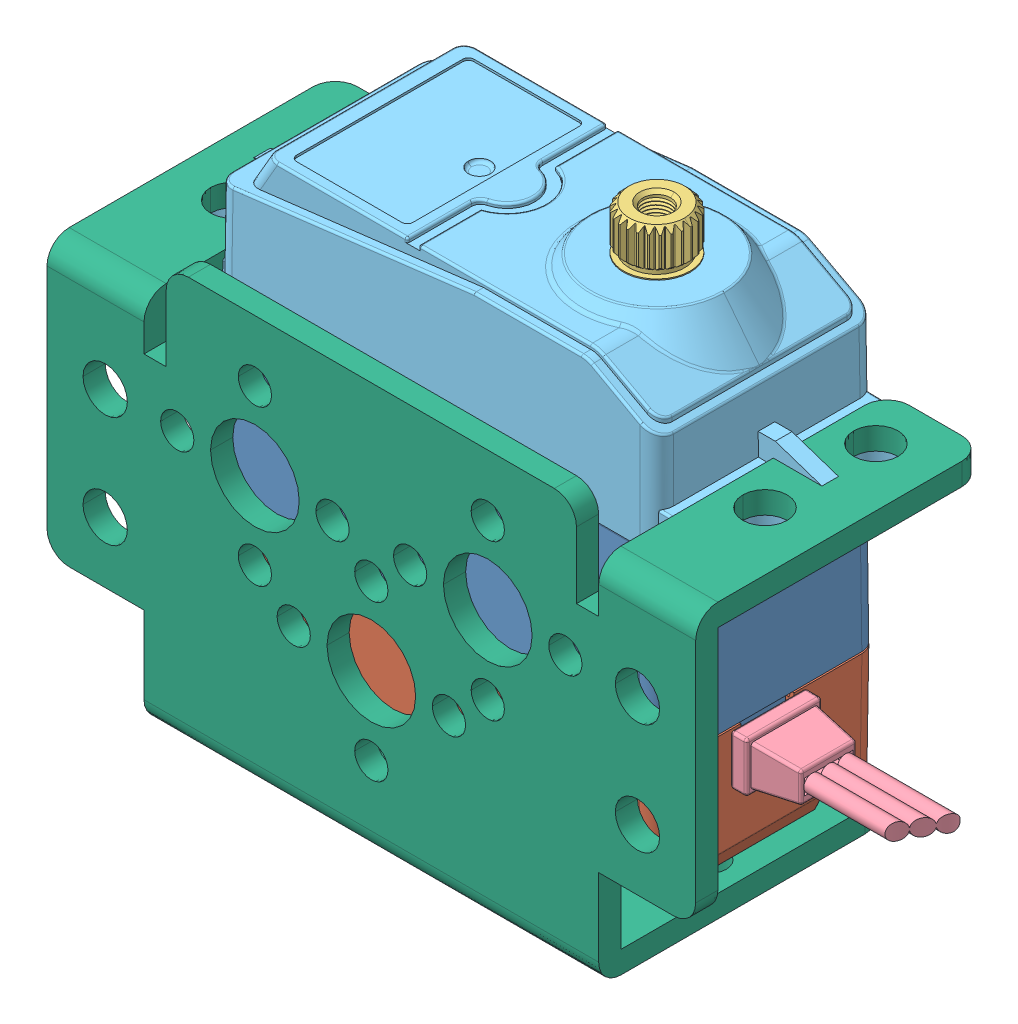
SolidWorks assembly 单轴舵机, configuration 默认. Lengths in mm.
Overall size (63.51 47.5 26.53).
9 component instances, 7 part files, 3 mates.
Components (placement in the parent):
- 单轴舵机.STEP-1: 单轴舵机.STEP [默认] at origin size (62.21 45.5 20.07)
  - DS3218(2)^单轴舵机.STEP-1: DS3218(2)^单轴舵机.STEP [默认] at (22.0661 -25.9401 -11.5148) size (62.21 45.5 20.07)
    - ZK^DS3218(2)_单轴舵机.STEP-1: ZK^DS3218(2)_单轴舵机.STEP [默认] at origin size (39.96 19.01 20.06)
    - DG-SZ^DS3218(2)_单轴舵机.STEP-1: DG-SZ^DS3218(2)_单轴舵机.STEP [默认] at origin size (39.97 10.96 20.07)
    - GE^DS3218(2)_单轴舵机.STEP-1: GE^DS3218(2)_单轴舵机.STEP [默认] at (10 10.9 0) x (1 0 0) z (0 -1 0) size (17.3 17.3 15.8)
    - XIANTAO^DS3218(2)_单轴舵机.STEP-1: XIANTAO^DS3218(2)_单轴舵机.STEP [默认] at (18.2007 -11.45 -0.1) size (18.31 4.5 6.8)
    - SG-JIANRONG-MG996^DS3218(2)_单轴舵机.STEP-1: SG-JIANRONG-MG996^DS3218(2)_单轴舵机.STEP [默认] at origin size (54.4 13.92 19.9)
- 舵盘-1: 舵盘 [默认] at (32.0661 1.5599 -11.5148) x (0.419272 0 0.907861) z (0.907861 0 -0.419272) (suppressed, hidden)
- 多功能支架-1: 多功能支架 [默认] at (22.8161 -28.9401 4.9852) x (-1 0 0) z (0 -1 0) size (58.5 26 37)
Mates (geometry in assembly coordinates):
- 重合2: coincident: plane of 单轴舵机.STEP-1/DS3218(2)^单轴舵机.STEP-1/DG-SZ^DS3218(2)_单轴舵机.STEP-1 through (22.0661 -45.9401 -11.5148) normal (0 -1 0); plane of 多功能支架-1 through (22.8161 -45.9401 4.9852) normal (0 1 0)
- 同心2: concentric: cylinder of 单轴舵机.STEP-1/DS3218(2)^单轴舵机.STEP-1/SG-JIANRONG-MG996^DS3218(2)_单轴舵机.STEP-1 through (46.8161 -11.5401 -16.5148) axis (0 1 0) radius 2.25; cylinder of 多功能支架-1 through (46.8161 -16.4401 -16.5148) axis (0 1 0) radius 2
- 垂直1: perpendicular: plane of 单轴舵机.STEP-1/DS3218(2)^单轴舵机.STEP-1/ZK^DS3218(2)_单轴舵机.STEP-1 through (2.216 -18.3411 -23.4435) normal (-0.999976 0.006981 0); plane of 多功能支架-1 through (22.8161 -28.9401 2.9852) normal (0 0 -1)
